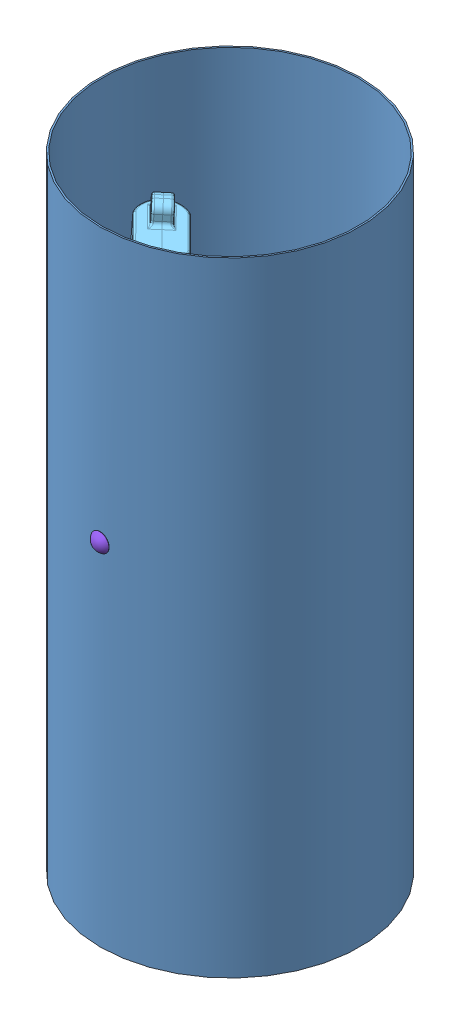
SolidWorks assembly Assembly With Actuator, configuration Default. Lengths in mm.
Overall size (135.74 305.7 165.85).
13 component instances, 9 part files, 13 mates.
Components (placement in the parent):
- BodyTube-1: BodyTube [Default] at (62.1605 30.2582 245.1643) size (127 304.8 127)
- EngineCasing-1: EngineCasing [Default] at (48.279 30.9242 249.9131) x (0.00222 0.027609 0.999616) z (-0.996783 0.080147 0) size (29 186.69 29)
- Gimbal Actuator Assembly-1: Gimbal Actuator Assembly [Default] at (178.1747 205.5862 257.0427) x (0.947819 0.317225 -0.03175) z (-0.091071 0.364848 0.926602) size (82.9 137.43 122.63)
  - Actuator to gimbal ring connector (Right)-1: Actuator to gimbal ring connector (Right) [Default] at (-137.3768 39.8489 39.3924) x (-0.672526 0 0.740074) z (-0.627624 0.529906 -0.57034) size (5.08 31.75 10.16)
  - GimbalRing-1: GimbalRing [Default] at (-114.5344 28.4551 -5.2372) x (-0.03175 -0.3747 0.926602) z (-0.919345 0.3747 0.12002) size (63.5 19.05 63.5)
  - p16_50mm_in(Actuator)-1: p16_50mm_in(Actuator) [Default] at (-94.7476 134.4076 52.964) x (-0.627624 0.529906 -0.57034) z (-0.392169 -0.848057 -0.356375) size (36.18 20.01 105.9)
  - Actuator Fastoning pin-1: Actuator Fastoning pin [Default] at (-133.1766 36.5329 22.7825) x (0.455319 -0.788344 0.413762) z (-0.672526 0 0.740074) size (4.68 4.68 11.71)
  - Actuator Fastoning pin-2: Actuator Fastoning pin [Default] at (-122.1663 50.0592 23.1781) x (0.048107 0.997885 0.043716) z (0.672526 0 -0.740074) size (4.68 4.68 11.71)
  - Actuator to gimbal ring connector (Left)-1: Actuator to gimbal ring connector (Left) [Default] at (-118.6369 45.2328 5.9586) x (0.672526 0 -0.740074) z (0.627624 -0.529906 0.57034) size (7.3 31.75 10.16)
- Quarter 20 bolt - Body Tube to Gimbal Ring - Copy-1: Quarter 20 bolt - Body Tube to Gimbal Ring - Copy [Default] at (62.1605 201.7082 305.3623) size (8.89 8.89 37.85)
- Quarter 20 bolt - Gimbal Ring to Engine Casing-1: Quarter 20 bolt - Gimbal Ring to Engine Casing [Default] at (93.8113 199.2005 245.1643) x (-0.010814 -0.134496 0.990855) z (-0.996783 0.080147 0) size (10.16 10.16 20.41)
- Quarter 20 bolt - Body Tube to Gimbal Ring - Copy-2: Quarter 20 bolt - Body Tube to Gimbal Ring - Copy [Default] at (62.1605 201.7082 184.9663) x (-0.243976 0.969781 0) z (0 0 -1) size (8.89 8.89 37.85)
- Quarter 20 bolt - Gimbal Ring to Engine Casing-2: Quarter 20 bolt - Gimbal Ring to Engine Casing [Default] at (30.2186 204.3137 245.1643) x (0.078818 0.980255 -0.18135) z (0.996783 -0.080147 0) size (10.16 10.16 20.41)
Mates (geometry in assembly coordinates):
- Concentric1: concentric: cylinder of EngineCasing-1 through (75.8353 200.6459 245.1643) axis (0.996783 -0.080147 0) radius 1.905; cylinder of Quarter 20 bolt - Gimbal Ring to Engine Casing-1 through (75.9619 200.6357 245.1643) axis (0.996783 -0.080147 0) radius 1.8415
- Concentric2: concentric: cylinder of Gimbal Actuator Assembly-1/GimbalRing-1 through (93.8113 199.2005 245.1643) axis (0.996783 -0.080147 0) radius 2.5527; cylinder of Quarter 20 bolt - Gimbal Ring to Engine Casing-1 through (76.4683 200.595 245.1643) axis (0.996783 -0.080147 0) radius 2.2225
- Tangent2: tangent: cylinder of Gimbal Actuator Assembly-1/GimbalRing-1 through (62.9269 211.2395 245.1643) axis (-0.080147 -0.996783 0) radius 31.75; plane of Quarter 20 bolt - Gimbal Ring to Engine Casing-1 through (93.8113 199.2005 245.1643) normal (-0.996783 0.080147 0)
- Tangent3: tangent: cylinder of EngineCasing-1 through (63.2359 216.9422 244.7422) axis (-0.080116 -0.996401 0.027698) radius 14.5; plane of Quarter 20 bolt - Gimbal Ring to Engine Casing-1 through (76.4683 200.595 245.1643) normal (-0.996783 0.080147 0)
- Concentric3: concentric: cylinder of Gimbal Actuator Assembly-1/GimbalRing-1 through (62.1605 201.7082 213.4143) axis (0 0 1) radius 1.905; cylinder of Quarter 20 bolt - Body Tube to Gimbal Ring - Copy-1 through (62.1605 201.7082 273.4853) axis (0 0 1) radius 1.905
- Tangent4: tangent: cylinder of Gimbal Actuator Assembly-1/GimbalRing-1 through (62.9269 211.2395 245.1643) axis (-0.080147 -0.996783 0) radius 31.75; plane of Quarter 20 bolt - Body Tube to Gimbal Ring - Copy-1 through (62.1605 201.7082 276.9143) normal (0 0 -1)
- Concentric4: concentric: cylinder of BodyTube-1 through (62.1605 201.7082 308.6643) axis (0 0 1) radius 2.5527; cylinder of Quarter 20 bolt - Body Tube to Gimbal Ring - Copy-1 through (62.1605 201.7082 276.9143) axis (0 0 1) radius 2.2225
- Tangent5: tangent: cylinder of BodyTube-1 through (62.1605 335.0582 245.1643) axis (0 -1 0) radius 63.5; plane of Quarter 20 bolt - Body Tube to Gimbal Ring - Copy-1 through (62.1605 201.7082 308.6643) normal (0 0 -1)
- Concentric6: concentric: cylinder of EngineCasing-1 through (48.1945 202.8683 245.1643) axis (-0.996783 0.080147 0) radius 1.905; cylinder of Quarter 20 bolt - Gimbal Ring to Engine Casing-2 through (48.068 202.8785 245.1643) axis (-0.996783 0.080147 0) radius 1.8415
- Tangent6: tangent: cylinder of EngineCasing-1 through (63.2359 216.9422 244.7422) axis (-0.080116 -0.996401 0.027698) radius 14.5; plane of Quarter 20 bolt - Gimbal Ring to Engine Casing-2 through (47.5616 202.9192 245.1643) normal (0.996783 -0.080147 0)
- Concentric7: concentric: cylinder of Gimbal Actuator Assembly-1/GimbalRing-1 through (62.1605 201.7082 213.4143) axis (0 0 1) radius 1.905; cylinder of Quarter 20 bolt - Body Tube to Gimbal Ring - Copy-2 through (62.1605 201.7082 216.8433) axis (0 0 -1) radius 1.905
- Tangent7: tangent: cylinder of Gimbal Actuator Assembly-1/GimbalRing-1 through (62.9269 211.2395 245.1643) axis (-0.080147 -0.996783 0) radius 31.75; plane of Quarter 20 bolt - Body Tube to Gimbal Ring - Copy-2 through (62.1605 201.7082 213.4143) normal (0 0 1)
- Lock1: lock: unknown of BodyTube-1; unknown of Quarter 20 bolt - Body Tube to Gimbal Ring - Copy-1
